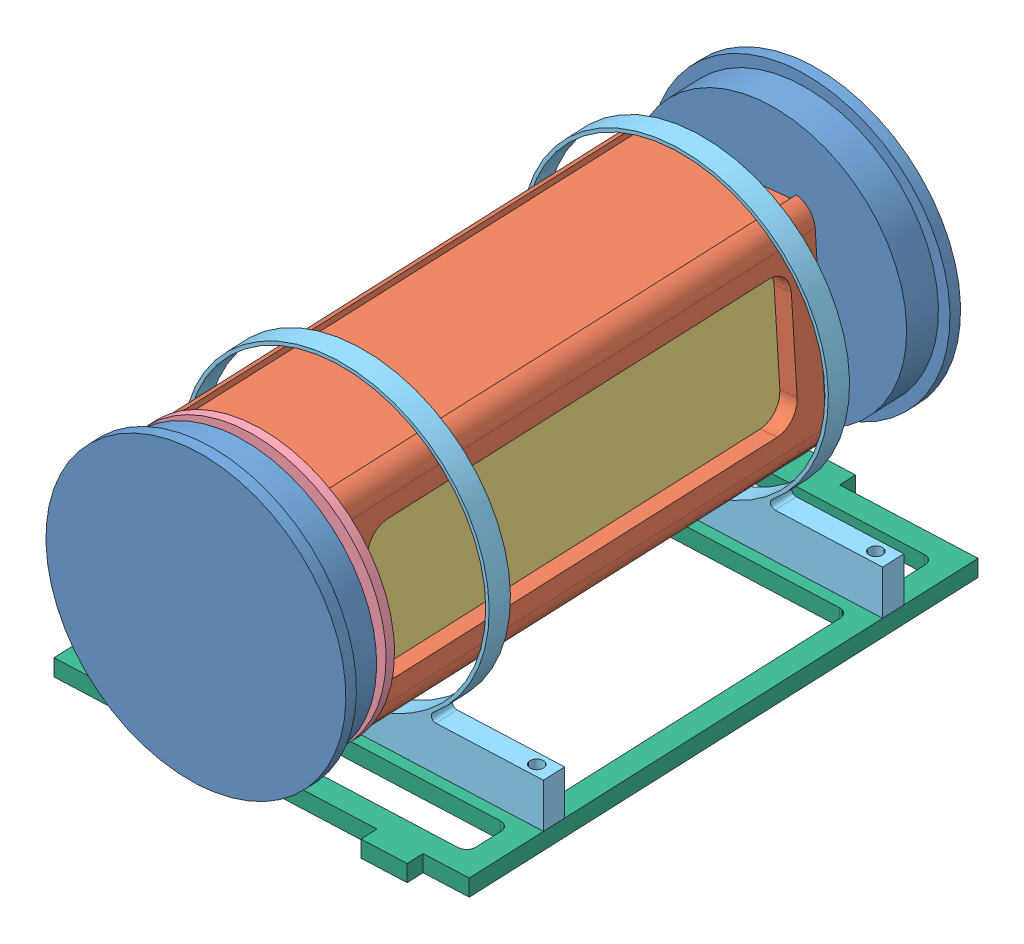
SolidWorks assembly Battery Pod Assem, configuration Default. Lengths in mm.
Overall size (122.12 96.18 193.65).
12 component instances, 8 part files, 6 mates.
Components (placement in the parent):
- Battery Pod-1: Battery Pod [Default] at (-218.7471 -21.6378 1.8894) x (0.997117 0.063072 -0.042191) z (0.042275 0 0.999106) size (82.55 82.55 184.15)
  - Battery Pod Tube-1: Battery Pod Tube [Default] at (30.9066 75.5653 -124.2248) size (82.55 82.55 177.8) (hidden)
  - Battery Pod Front Lid-1: Battery Pod Front Lid [Default] at (30.9066 75.5653 53.5752) x (1 0 0) z (0 -1 0) size (82.55 12.7 82.55)
  - Battery Holder-1: Battery Holder [Default] at (87.4904 45.3624 -37.9532) size (52.45 60.64 142.88)
    - Battery Holder-1: Battery Holder [Default] at (-82.8093 -0.1184 78.8907) size (52.45 60.64 142.88)
    - Battery-1: Battery [Default] at (-56.5838 1.4691 8.7232) x (0 0 -1) z (1 0 0) size (135.89 55.88 42.93)
  - Battery Board-1: Battery Board [Default] at (30.9066 75.5653 38.715) size (76.2 76.2 2.54)
  - Battery Pod Front Lid-2: Battery Pod Front Lid [Default] at (30.9066 75.5653 -124.2248) x (1 0 0) z (0 1 0) size (82.55 12.7 82.55)
  - Battery Board 2-1: Battery Board 2 [Default] at (4.6811 75.3397 -44.511) x (0 0 -1) z (0 1 0) size (100.33 1.59 58.42)
- Quick Release Mount-3: Quick Release Mount [Default] at (-192.3326 55.7264 9.2666) x (0.999106 0 -0.042275) z (0.042275 0 0.999106) size (114.3 89.85 6.35)
- Quick Release Mount-4: Quick Release Mount [Default] at (-196.6278 55.7264 -92.2425) x (0.999106 0 -0.042275) z (0.042275 0 0.999106) size (114.3 89.85 6.35)
- Battery Panel-1: Battery Panel [Default] at (-194.3459 8.1014 -38.3158) x (0.999106 0 -0.042275) z (-0.042275 0 -0.999106) size (114.3 4.76 187.33)
Mates (geometry in assembly coordinates):
- Parallel1: parallel aligned: line of Quick Release Mount-4 through (-139.5289 20.8014 -94.6586) axis (-0.999106 0 0.042275); line of Battery Panel-1 through (-143.7131 3.3389 16.7429) axis (-0.999106 0 0.042275)
- Concentric1: concentric anti-aligned: cylinder of Battery Pod-1/Battery Pod Tube-1 through (-190.4265 55.7264 54.3142) axis (-0.042275 0 -0.999106) radius 41.275; circle of Quick Release Mount-3
- Coincident3: coincident anti-aligned: plane of Quick Release Mount-3 through (-134.9652 8.1014 13.1949) normal (0 -1 0); plane of Battery Panel-1 through (-255.2031 8.1014 -124.7203) normal (0 1 0)
- Concentric2: concentric aligned: circle of Quick Release Mount-3; circle of Battery Panel-1
- Concentric3: concentric aligned: circle of Quick Release Mount-4; circle of Battery Panel-1
- Concentric4: concentric anti-aligned: cylinder of Battery Pod-1/Battery Pod Tube-1 through (-190.4265 55.7264 54.3142) axis (-0.042275 0 -0.999106) radius 41.275; circle of Quick Release Mount-4
